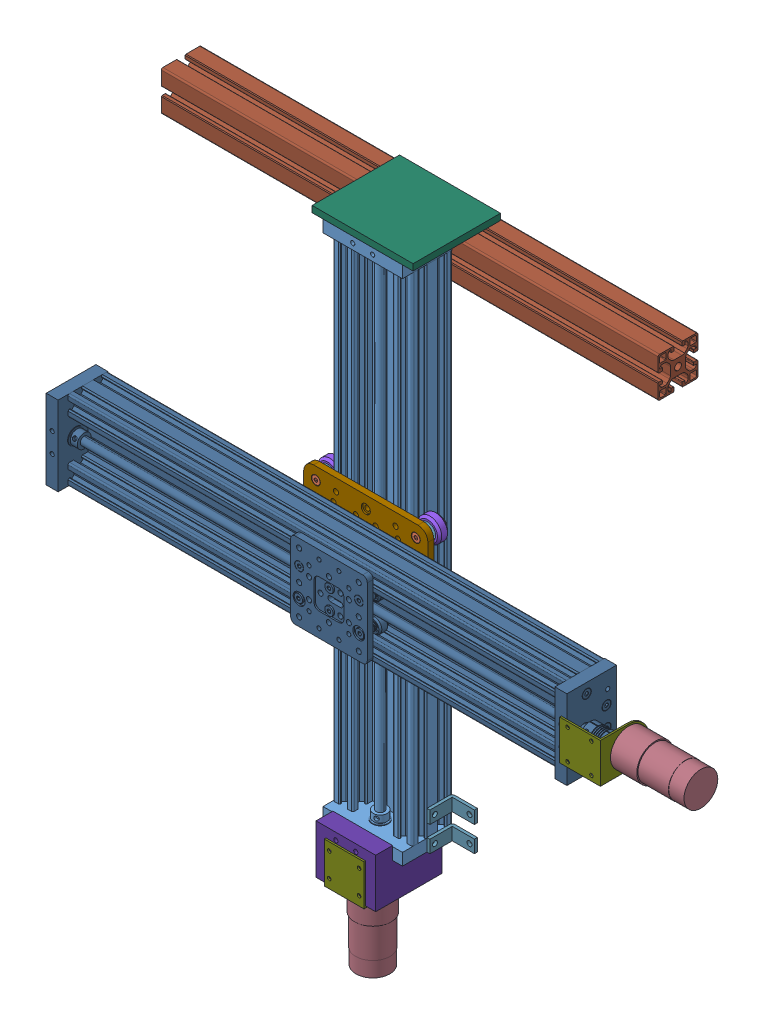
SolidWorks assembly Ensamblaje del Arreglo 1, configuration Predeterminado. Lengths in mm.
Overall size (634.13 640.96 140.75).
58 component instances, 21 part files, 11 mates.
Components (placement in the parent):
- C-Beam Actuator Lineal 500mm (Sin motor, sin carrito)-1: C-Beam Actuator Lineal 500mm (Sin motor, sin carrito) [Predeterminado] at (-63.6915 -221.1553 511.0582) size (80 554.4 50)
- XLarge C-Beam Gantry Kit-1: XLarge C-Beam Gantry Kit [Predeterminado] at (-37.1117 -46.768 573.4175) x (1 0 0) z (0 -1 0) size (125 27.2 125)
  - XLarge C-Beam Gantry Kit.step-1: XLarge C-Beam Gantry Kit.step [Predeterminado] at origin size (125 27.2 125)
    - Low Profile Screw M5 v1.step-1: Low Profile Screw M5 v1.step [Predeterminado] at (50.3 -18.5598 -47.3741) x (0 -1 0) z (0 0 -1) size (27 9 9)
    - Nylon Insert Lock Nut M5.step-1: Nylon Insert Lock Nut M5.step [Predeterminado] at (50.3 -19.1598 -47.3741) x (1 0 0) z (0 0 -1) size (8 5 9.24)
    - Aluminum Spacer 6mm.step-1: Aluminum Spacer 6mm.step [Predeterminado] at (50.3 -2.9598 -47.3741) x (1 0 0) z (0 -1 0) size (10 10 6)
    - Ball Bearing 5 x 16 x 5.step-1: Ball Bearing 5 x 16 x 5.step [Predeterminado] at (50.3 -11.4598 -47.3741) x (0 -1 0) z (0 0 -1) size (5 16 16)
    - Precision Shim 8 x 5 x 1.step-1: Precision Shim 8 x 5 x 1.step [Predeterminado] at (50.3 -13.5598 -47.3741) x (1 0 0) z (0 0 -1) size (8 1 8)
    - Ball Bearing 5 x 16 x 5.step-2: Ball Bearing 5 x 16 x 5.step [Predeterminado] at (50.3 -16.6598 -47.3741) x (0 -1 0) z (0 0 -1) size (5 16 16)
    - Low Profile Screw M5 v1.step-2: Low Profile Screw M5 v1.step [Predeterminado] at (-50.3 -18.5598 53.2259) x (0 -1 0) z (0 0 -1) size (27 9 9)
    - Nylon Insert Lock Nut M5.step-2: Nylon Insert Lock Nut M5.step [Predeterminado] at (-50.3 -19.1598 53.0159) x (-1 0 0) z (0 0 1) size (8 5 9.24)
    - Ball Bearing 5 x 16 x 5.step-3: Ball Bearing 5 x 16 x 5.step [Predeterminado] at (-50.3 -11.4598 53.0159) x (0 -1 0) z (0 0 1) size (5 16 16)
    - Precision Shim 8 x 5 x 1.step-2: Precision Shim 8 x 5 x 1.step [Predeterminado] at (-50.3 -13.5598 53.0159) x (-1 0 0) z (0 0 1) size (8 1 8)
    - Ball Bearing 5 x 16 x 5.step-4: Ball Bearing 5 x 16 x 5.step [Predeterminado] at (-50.3 -16.6598 53.0159) x (0 -1 0) z (0 0 1) size (5 16 16)
    - Eccentric Spacer 6mm v1.step-1: Eccentric Spacer 6mm v1.step [Predeterminado] at (-50.3 -2.9598 53.2259) x (-1 0 0) z (0 0 1) size (11.55 8.5 10)
    - Xtreme Solid V Wheel.step-1: Xtreme Solid V Wheel.step [Predeterminado] at (50.3 -14.0598 -47.3741) x (0 -1 0) z (0 0 1) size (10.2 23.9 23.9)
    - Xtreme Solid V Wheel.step-2: Xtreme Solid V Wheel.step [Predeterminado] at (-50.3 -14.0598 53.0159) x (0 -1 0) z (0 0 1) size (10.2 23.9 23.9)
    - C-Beam Gantry Plate XLarge.step-1: C-Beam Gantry Plate XLarge.step [Predeterminado] at (0 -2.9598 2.9259) x (1 0 0) z (0 1 0) size (125 125 6)
    - Eccentric Spacer 6mm v1.step-2: Eccentric Spacer 6mm v1.step [Predeterminado] at (50.3 -2.9598 53.2259) x (-1 0 0) z (0 0 1) size (11.55 8.5 10)
    - Xtreme Solid V Wheel.step-3: Xtreme Solid V Wheel.step [Predeterminado] at (50.3 -14.0598 53.0159) x (0 -1 0) z (0 0 1) size (10.2 23.9 23.9)
    - Nylon Insert Lock Nut M5.step-3: Nylon Insert Lock Nut M5.step [Predeterminado] at (50.3 -19.1598 53.0159) x (-1 0 0) z (0 0 1) size (8 5 9.24)
    - Low Profile Screw M5 v1.step-3: Low Profile Screw M5 v1.step [Predeterminado] at (50.3 -18.5598 53.2259) x (0 -1 0) z (0 0 -1) size (27 9 9)
    - Ball Bearing 5 x 16 x 5.step-5: Ball Bearing 5 x 16 x 5.step [Predeterminado] at (50.3 -11.4598 53.0159) x (0 -1 0) z (0 0 1) size (5 16 16)
    - Precision Shim 8 x 5 x 1.step-3: Precision Shim 8 x 5 x 1.step [Predeterminado] at (50.3 -13.5598 53.0159) x (-1 0 0) z (0 0 1) size (8 1 8)
    - Ball Bearing 5 x 16 x 5.step-6: Ball Bearing 5 x 16 x 5.step [Predeterminado] at (50.3 -16.6598 53.0159) x (0 -1 0) z (0 0 1) size (5 16 16)
    - Nylon Insert Lock Nut M5.step-4: Nylon Insert Lock Nut M5.step [Predeterminado] at (-50.3 -19.1598 -47.3741) x (1 0 0) z (0 0 -1) size (8 5 9.24)
    - Aluminum Spacer 6mm.step-2: Aluminum Spacer 6mm.step [Predeterminado] at (-50.3 -2.9598 -47.3741) x (1 0 0) z (0 -1 0) size (10 10 6)
    - Ball Bearing 5 x 16 x 5.step-7: Ball Bearing 5 x 16 x 5.step [Predeterminado] at (-50.3 -11.4598 -47.3741) x (0 -1 0) z (0 0 -1) size (5 16 16)
    - Low Profile Screw M5 v1.step-4: Low Profile Screw M5 v1.step [Predeterminado] at (-50.3 -18.5598 -47.3741) x (0 -1 0) z (0 0 -1) size (27 9 9)
    - Precision Shim 8 x 5 x 1.step-4: Precision Shim 8 x 5 x 1.step [Predeterminado] at (-50.3 -13.5598 -47.3741) x (1 0 0) z (0 0 -1) size (8 1 8)
    - Ball Bearing 5 x 16 x 5.step-8: Ball Bearing 5 x 16 x 5.step [Predeterminado] at (-50.3 -16.6598 -47.3741) x (0 -1 0) z (0 0 -1) size (5 16 16)
    - Xtreme Solid V Wheel.step-4: Xtreme Solid V Wheel.step [Predeterminado] at (-50.3 -14.0598 -47.3741) x (0 -1 0) z (0 0 1) size (10.2 23.9 23.9)
- C-Beam Actuator Lineal 500mm (Sin motor)-1: C-Beam Actuator Lineal 500mm (Sin motor) [Predeterminado] at (146.9874 -75.8771 557.9746) x (0 1 0) z (0 0 1) size (80 554.4 50)
- Perfil de Aluminio-1: Perfil de Aluminio [Predeterminado] at (-289.6405 -269.2729 529.3906) x (0 0 -1) z (1 0 0) size (40 40 500) (hidden)
- Perfil de Aluminio-2: Perfil de Aluminio [Predeterminado] at (-289.9546 214.7699 529.372) x (0 0 -1) z (1 0 0) size (40 40 500)
- Tubito-1: Tubito [Predeterminado] at (-63.7036 -221.0873 511.0866) size (10.11 40 10.11) (hidden)
- Tubito-2: Tubito [Predeterminado] at (-110.8688 -221.0882 511.0776) size (10.11 40 10.11) (hidden)
- Clavo-1: Clavo [Predeterminado] at (-16.5353 -221.3137 511.0835) size (9 56.5 9) (hidden)
- Clavo-2: Clavo [Predeterminado] at (-63.7185 -221.2206 511.0591) size (9 56.5 9)
- Gearmotor_37D_19a1-4: Gearmotor_37D_19a1 [Predeterminado] at (-37.1688 -327.2313 569.2701) x (0 1 0) z (1 0 0) size (94.6 36.8 36.8)
- Perfil de Aluminio 40x40-5: Perfil de Aluminio 40x40 [Predeterminado] at (-57.4819 -389.2812 509.4) x (1 0 0) z (0 1 0) size (40 40 100) (hidden)
- SoleraAluminio-1: SoleraAluminio [Predeterminado] at (13.9594 -289.274 549.702) x (-1 0 0) z (0 -1 0) size (101.6 60 6.4) (hidden)
- Escuadra-1: Escuadra [Predeterminado] at (-17.4732 -295.707 525.2486) x (1 0 0) z (0 -1 0) size (25.4 12.7 25.4) (hidden)
- Escuadra-2: Escuadra [Predeterminado] at (-17.4901 -295.6951 502.0444) x (1 0 0) z (0 -1 0) size (25.4 12.7 25.4) (hidden)
- Escuadra-3: Escuadra [Predeterminado] at (-57.5043 -295.7172 525.4765) x (0 -1 0) z (-1 0 0) size (25.4 12.7 25.4) (hidden)
- Escuadra-7: Escuadra [Predeterminado] at (-57.479 -295.7047 502.0257) x (0 -1 0) z (-1 0 0) size (25.4 12.7 25.4) (hidden)
- Escuadra-8: Escuadra [Predeterminado] at (2.8086 -289.2671 529.3861) size (25.4 12.7 25.4)
- Escuadra-9: Escuadra [Predeterminado] at (2.7469 -263.8725 529.3905) size (25.4 12.7 25.4)
- Escuadra-10: Escuadra [Predeterminado] at (-77.2995 -276.5609 529.41) x (-1 0 0) z (0 0 1) size (25.4 12.7 25.4)
- Escuadra-11: Escuadra [Predeterminado] at (-77.2482 -251.4285 529.4041) x (-1 0 0) z (0 0 1) size (25.4 12.7 25.4)
- Solera-1: Solera [Predeterminado] at (-88.2075 234.7333 491.3824) size (101.6 6.4 88)
- Gearmotor_37D_19a1-5: Gearmotor_37D_19a1 [Predeterminado] at (252.6383 -49.5287 601.5546) x (-1 0 0) z (0 -1 0) size (94.6 36.8 36.8)
- SoleraBase-1: SoleraBase [Predeterminado] at (197.0701 -99.73 566.174) x (0 1 0) z (1 0 0) size (101.6 6.4 100) (hidden)
- Escuadra-12: Escuadra [Predeterminado] at (215.1217 -79.8042 572.9445) size (25.4 12.7 25.4) (hidden)
- Escuadra-13: Escuadra [Predeterminado] at (215.1296 -32.4986 572.9517) size (25.4 12.7 25.4) (hidden)
- Bracket-3: Bracket [Predeterminado] at (-17.2438 -286.2313 598.1) x (0 -1 0) z (0 0 -1) size (41 40 48.7)
- Bracket-4: Bracket [Predeterminado] at (211.6383 -29.4537 630.1247) x (1 0 0) z (0 0 -1) size (41 40 48.7)
- Impresion3D-1: Impresion3D [Predeterminado] at (-57.2438 -325.5313 596.4) x (0 1 0) z (-1 0 0) size (49.25 67 60)
Mates (geometry in assembly coordinates):
- Paralelo1: parallel anti-aligned: line of Perfil de Aluminio-1 through (210.3595 -287.7729 489.3906) axis (0 1 0); line of Perfil de Aluminio 40x40-5 through (-18.9819 -289.2812 489.4) axis (0 -1 0)
- Concéntrica2: concentric anti-aligned: cylinder of Gearmotor_37D_19a1-4 through (-44.9188 -327.2313 582.6935) axis (0 -1 0) radius 1.5; cylinder of Bracket-3 through (-44.9188 -335.5313 582.6935) axis (0 1 0) radius 1.5
- Paralelo2: parallel anti-aligned: cylinder of Gearmotor_37D_19a1-4 through (-29.4188 -327.2313 582.6935) axis (0 -1 0) radius 1.5; cylinder of Bracket-3 through (-29.5688 -335.5313 582.6935) axis (0 1 0) radius 1.5
- Coincidente1: coincident anti-aligned: plane of Gearmotor_37D_19a1-4 through (-37.1688 -327.2313 569.2701) normal (0 1 0); plane of Bracket-3 through (-17.2438 -327.2313 596.4) normal (0 -1 0)
- Concéntrica4: concentric anti-aligned: cylinder of Gearmotor_37D_19a1-5 through (252.6383 -41.7787 588.1312) axis (1 0 0) radius 1.5; cylinder of Bracket-4 through (260.9383 -41.7787 588.1312) axis (-1 0 0) radius 1.5
- Paralelo3: parallel anti-aligned: cylinder of Gearmotor_37D_19a1-5 through (252.6383 -57.2787 588.1312) axis (1 0 0) radius 1.5; cylinder of Bracket-4 through (260.9383 -57.1287 588.1312) axis (-1 0 0) radius 1.5
- Coincidente2: coincident anti-aligned: plane of Gearmotor_37D_19a1-5 through (252.6383 -49.5287 601.5546) normal (-1 0 0); plane of Bracket-4 through (252.6383 -29.4537 628.4247) normal (1 0 0)
- Coincidente5: coincident anti-aligned: plane of Bracket-3 through (-17.2438 -325.5313 536.4) normal (0 1 0); plane of Impresion3D-1 through (-17.2438 -325.5313 579.4) normal (0 -1 0)
- Concéntrica7: concentric aligned: cylinder of Bracket-3 through (-22.2438 -318.2313 596.4) axis (0 0 1) radius 1.8; cylinder of Impresion3D-1 through (-22.2438 -318.2313 579.4) axis (0 0 1) radius 1.8
- Coincidente6: coincident anti-aligned: plane of Bracket-3 through (-17.2438 -286.2313 596.4) normal (0 0 -1); plane of Impresion3D-1 through (-57.2438 -325.5313 596.4) normal (0 0 1)
- Tangente2: tangent: cylinder of assembly; face of C-Beam Actuator Lineal 500mm (Sin motor, sin carrito)-1; cylinder of Impresion3D-1 through (-27.2438 -283.2813 579.4) axis (0 0 1) radius 2.1
